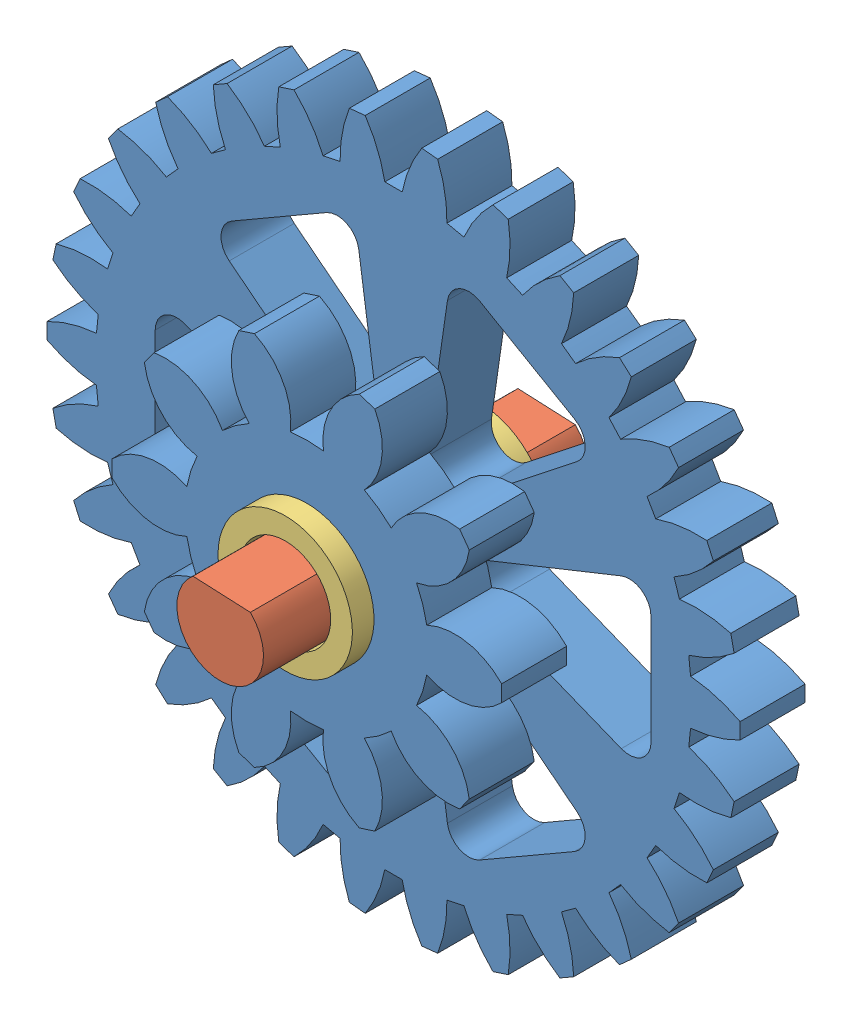
SolidWorks assembly assem2, configuration Default. Lengths in mm.
Overall size (32 31.89 15).
6 component instances, 3 part files, 12 mates.
Components (placement in the parent):
- Root_gear-1: Root_gear [30T 1.0Mod] at (10.8888 18.1177 22.6563) size (32 31.89 3)
- Root_gear-2: Root_gear [10T 1.5Mod] at (10.8888 18.1177 26.6563) size (18 17.34 3)
- axel-1: axel [15mm] at (10.8888 18.1177 18.6563) x (0.998946 -0.045893 0) z (0 0 1) size (4 3.5 15)
- spacer-1: spacer [1mm] at (10.8888 18.1177 21.6563) size (6.2 6.2 1)
- spacer-2: spacer [1mm] at (10.8888 18.1177 25.6563) x (0.999924 0.012321 0) z (0 0 1) size (6.2 6.2 1)
- spacer-3: spacer [1mm] at (10.8888 18.1177 29.6563) size (6.2 6.2 1)
Mates (geometry in assembly coordinates):
- Concentric1: concentric anti-aligned: cylinder of Root_gear-1 through (10.8888 18.1177 22.6563) axis (0 0 1) radius 2; cylinder of axel-1 through (10.8888 18.1177 33.6563) axis (0 0 -1) radius 2
- Concentric2: concentric anti-aligned: cylinder of Root_gear-2 through (10.8888 18.1177 26.6563) axis (0 0 1) radius 2; cylinder of axel-1 through (10.8888 18.1177 33.6563) axis (0 0 -1) radius 2
- Concentric3: concentric aligned: cylinder of axel-1 through (10.8888 18.1177 33.6563) axis (0 0 -1) radius 2; cylinder of spacer-2 through (10.8888 18.1177 26.6563) axis (0 0 -1) radius 2.1
- Concentric4: concentric aligned: cylinder of axel-1 through (10.8888 18.1177 33.6563) axis (0 0 -1) radius 2; cylinder of spacer-3 through (10.8888 18.1177 30.6563) axis (0 0 -1) radius 2.1
- Concentric5: concentric aligned: cylinder of axel-1 through (10.8888 18.1177 33.6563) axis (0 0 -1) radius 2; cylinder of spacer-1 through (10.8888 18.1177 22.6563) axis (0 0 -1) radius 2.1
- Coincident1: coincident anti-aligned: plane of Root_gear-2 through (10.8888 18.1177 29.6563) normal (0 0 1); plane of spacer-3 through (10.8888 18.1177 29.6563) normal (0 0 -1)
- Parallel1: parallel aligned: line of Root_gear-2 through (12.2791 19.5554 26.6563) axis (-0.998946 0.045893 0); line of axel-1 through (12.2812 19.5535 33.6563) axis (-0.998946 0.045893 0)
- Parallel2: parallel: line of Root_gear-1 through (12.2791 19.5554 22.6563) axis (-0.998946 0.045893 0); plane of axel-1 through (9.634 19.6751 33.6563) normal (0.045893 0.998946 0)
- Coincident4: coincident anti-aligned: plane of Root_gear-1 through (10.8888 18.1177 22.6563) normal (0 0 -1); plane of spacer-1 through (10.8888 18.1177 22.6563) normal (0 0 1)
- Coincident5: coincident anti-aligned: plane of Root_gear-1 through (10.8888 18.1177 25.6563) normal (0 0 1); plane of spacer-2 through (10.8888 18.1177 25.6563) normal (0 0 -1)
- Coincident6: coincident anti-aligned: plane of Root_gear-2 through (10.8888 18.1177 26.6563) normal (0 0 -1); plane of spacer-2 through (10.8888 18.1177 26.6563) normal (0 0 1)
- Distance1: distance = 3 mm: line of axel-1 through (12.2812 19.5535 33.6563) axis (-0.998946 0.045893 0); plane of spacer-3 through (10.8888 18.1177 30.6563) normal (0 0 1)
